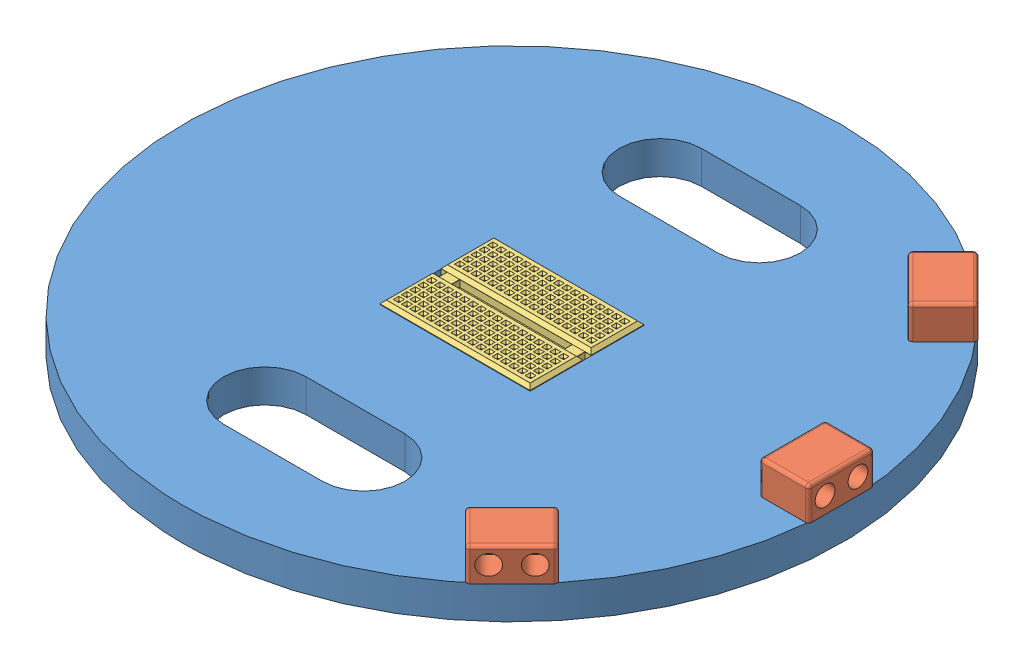
SolidWorks assembly Bot, configuration Default. Lengths in mm.
Overall size (200 20 200).
5 component instances, 3 part files, 8 mates.
Components (placement in the parent):
- base-1: base [Default] at (74.5647 92.9614 157.9191) size (200 10 200)
- LED_casing-1: LED_casing [Default] at (167.0647 102.9614 157.9191) x (0 0 -1) z (1 0 0) size (20 10 15)
- LED_casing-2: LED_casing [Default] at (139.9721 102.9614 223.3265) x (0.707107 0 -0.707107) z (0.707107 0 0.707107) size (20 10 15)
- LED_casing-3: LED_casing [Default] at (139.9721 102.9614 92.5118) x (-0.707107 0 -0.707107) z (0.707107 0 -0.707107) size (20 10 15)
- MiniBreadboard-1: MiniBreadboard [Default] at (74.5647 95.9614 157.9191) x (0 0 1) z (-1 0 0) size (34.6 8.15 45.6)
Mates (geometry in assembly coordinates):
- Parallel2: parallel: plane of base-1 through (74.5647 102.9614 157.9191) normal (0 1 0); plane of LED_casing-1 through (167.0647 102.9614 157.9191) normal (0 -1 0)
- Coincident6: coincident: circle of base-1; moEndPointRef_w of LED_casing-1
- Tangent3: tangent: cylinder of base-1 through (74.5647 102.9614 157.9191) axis (0 -1 0) radius 100; line of LED_casing-1 through (174.5647 102.9614 166.9191) axis (0 0 -1)
- Tangent4: tangent: cylinder of base-1 through (74.5647 102.9614 157.9191) axis (0 -1 0) radius 100; plane of LED_casing-1 through (174.5647 112.9614 167.9191) normal (1 0 0)
- Parallel6: parallel: plane of base-1 through (74.5647 92.9614 157.9191) normal (1 0 0); plane of LED_casing-1 through (174.5647 112.9614 167.9191) normal (1 0 0)
- Coincident7: coincident: line of base-1 through (51.7647 95.9614 140.6191) axis (0 0 1); line of MiniBreadboard-1 through (51.7647 95.9614 140.6191) axis (0 0 1)
- Coincident8: coincident: plane of base-1 through (74.5647 95.9614 157.9191) normal (0 1 0); plane of MiniBreadboard-1 through (51.7647 95.9614 175.2191) normal (0 -1 0)
- Coincident9: coincident: line of base-1 through (51.7647 95.9614 175.2191) axis (1 0 0); line of MiniBreadboard-1 through (51.7647 95.9614 175.2191) axis (1 0 0)
